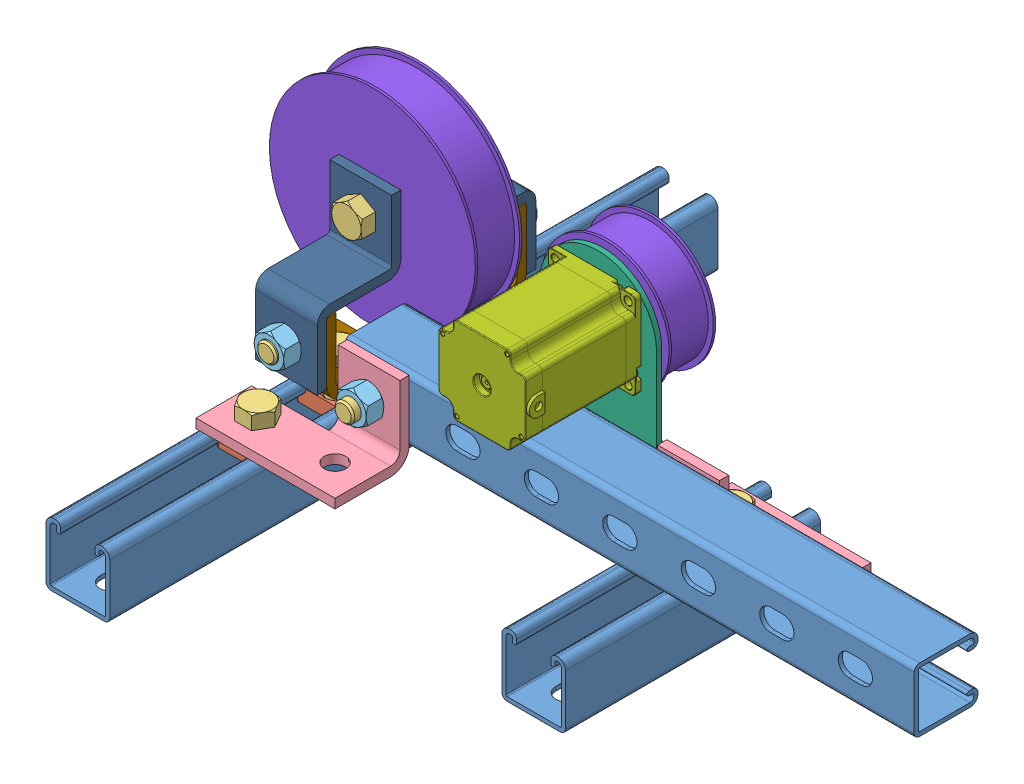
SolidWorks assembly Upper Pully System, configuration Default. Lengths in mm.
Overall size (490.87 222.78 393.7).
43 component instances, 10 part files, 44 mates.
Components (placement in the parent):
- P1000T - Unistrut Channel (Slots)-1: P1000T - Unistrut Channel (Slots) [0'-6.5"] at (-290.6524 -105.3852 -315.3895) size (41.28 41.27 165.1)
- Channel Nut-1: Channel Nut [P2223] at (-290.5427 -89.1071 -443.5385) x (1 0 0) z (0 1 0) size (34.99 19.63 34.65)
  - P3013 - Channel Nut-3: P3013 - Channel Nut [.5"] at origin size (34.99 19.63 9.53)
  - hex bolt_ai-1: hex bolt_ai [HBOLT 0.5000-13x1x1-N] at (0 0 19.555) x (0 0 -1) z (0 -1 0) size (34.65 22 19.05)
- P1000T - Unistrut Channel (Slots)-2: P1000T - Unistrut Channel (Slots) [1'-2.5"] at (-471.5246 -53.733 -394.9011) x (0.000688 1 0) z (-1 0.000688 0) size (41.28 41.27 368.3)
- Channel Nut-2: Channel Nut [P2223] at (-290.5427 -53.7478 -411.1791) x (0.000688 1 0) z (0 0 -1) size (34.99 19.63 34.65)
  - P3013 - Channel Nut-3: P3013 - Channel Nut [.5"] at origin size (34.99 19.63 9.53)
  - hex bolt_ai-1: hex bolt_ai [HBOLT 0.5000-13x1x1-N] at (0 0 19.555) x (0 0 -1) z (0 -1 0) size (34.65 22 19.05)
- P1038 - Unistrut 3-Hole 90 deg Fitting Variant-1: P1038 - Unistrut 3-Hole 90 deg Fitting Variant [Default] at (-220.5427 -84.7478 -463.5385) x (1 0 0) z (0 -1 0) size (90 48 51)
- P1000T - Unistrut Channel (Slots)-3: P1000T - Unistrut Channel (Slots) [1'-3.5"] at (-500.2028 -105.3852 -229.9119) size (41.28 41.27 393.7)
- Channel Nut-3: Channel Nut [P2245] at (-500.0933 -89.1071 -346.2637) x (1 0 0) z (0 1 0) size (34.99 19.63 34.65)
  - P3013 - Channel Nut-3: P3013 - Channel Nut [.5"] at origin size (34.99 19.63 9.53)
  - hex bolt_ai-1: hex bolt_ai [HBOLT 0.5000-13x1x1-N] at (0 0 19.9549) x (0 0 -1) z (0 -1 0) size (34.65 22 19.05)
- P1038 - Unistrut 3-Hole 90 deg Fitting Variant-2: P1038 - Unistrut 3-Hole 90 deg Fitting Variant [Default] at (-520.0933 -84.7478 -326.2637) x (-1 0 0) z (0 -1 0) size (90 48 51)
- hex bolt_ai-2: hex bolt_ai [HBOLT 0.5000-13x1x1-N] at (-450.0933 -53.7478 -386.1763) x (0 0 1) z (-1 0.000688 0) size (34.65 22 19.05)
- hex nut_ai-2: hex nut_ai [HNUT 0.5000-20-D-N] at (-450.0933 -53.7478 -356.8845) x (1 -0.000688 0) z (0 0 1) size (19.05 22 11.38)
- Channel Nut-4: Channel Nut [P2245+P1346] at (-500.0933 -89.1071 -473.178) x (1 0 0) z (0 1 0) size (34.99 19.63 35.49)
  - P3013 - Channel Nut-3: P3013 - Channel Nut [.5"] at origin size (34.99 19.63 9.53)
  - hex bolt_ai-1: hex bolt_ai [HBOLT 0.5000-13x1x1-N] at (0 0 25.9549) x (0 0 -1) z (0 -1 0) size (34.65 22 19.05)
- stepper motor mount-1: stepper motor mount [Default] at (-349.3295 17.8284 -418.8405) x (-1 0.000681 0) z (0 0 1) size (76.2 127 3.3)
- Channel Nut-5: Channel Nut [P2223] at (-325.8084 -53.9427 -411.1791) x (-0.000688 -1 0) z (0 0 -1) size (34.99 19.63 34.65)
  - P3013 - Channel Nut-3: P3013 - Channel Nut [.5"] at origin size (34.99 19.63 9.53)
  - hex bolt_ai-1: hex bolt_ai [HBOLT 0.5000-13x1x1-N] at (0 0 19.555) x (0 0 -1) z (0 -1 0) size (34.65 22 19.05)
- Channel Nut-6: Channel Nut [P2223] at (-372.9484 -53.9106 -411.1791) x (-0.000688 -1 0) z (0 0 -1) size (34.99 19.63 34.65)
  - P3013 - Channel Nut-3: P3013 - Channel Nut [.5"] at origin size (34.99 19.63 9.53)
  - hex bolt_ai-1: hex bolt_ai [HBOLT 0.5000-13x1x1-N] at (0 0 19.555) x (0 0 -1) z (0 -1 0) size (34.65 22 19.05)
- Stepper Motor NEMA 23HS7430-1: Stepper Motor NEMA 23HS7430 [По умолчанию] at (-349.3295 17.8284 -415.5385) x (1 -0.000681 0) z (0 0 1) size (58.4 56.4 95.6)
- Wide Pulley-1: Wide Pulley [3"x0.25"] at (-349.3295 17.8284 -435.5092) size (82.55 82.55 30.16)
- Large Pulley Mount-1: Large Pulley Mount [Default] at (-485.3304 -93.9054 -373.5693) x (0 1 0) z (1 0 0) size (187.97 168.14 187.97)
  - P1026 - Unistrut 2-Hole 90 deg Fitting-1: P1026 - Unistrut 2-Hole 90 deg Fitting [Default] at (18.6827 -44.2712 5.2371) size (50 47 40)
  - P1347 - Unistrut 2-Hole Z Fitting-1: P1347 - Unistrut 2-Hole Z Fitting [Default] at (28.6827 8.7288 -34.7629) x (1 0 0) z (0 0 -1) size (88 54 40)
  - hex bolt_ai-3: hex bolt_ai [HBOLT 0.5000-13x1x1-N] at (48.6827 -12.5168 -14.7629) x (0 1 0) z (0 0 1) size (34.65 22 19.05)
  - hex nut_ai-2: hex nut_ai [HNUT 0.5000-20-D-N] at (48.6827 20.108 -14.7629) x (0.866025 0 -0.5) z (0 1 0) size (19.05 22 11.38)
  - Wide Pulley-2: Wide Pulley [5"x0.5"] at (96.6827 -61.9399 -14.7629) x (0.762017 0 -0.647557) z (0 -1 0) size (133.35 133.35 30.16)
  - hex bolt_ai-2: hex bolt_ai [HBOLT 0.5000-20x3x3-N] at (96.6827 -30.0256 -14.7629) x (0 -1 0) z (0 0 1) size (85.45 22 19.05)
  - P1026 - Unistrut 2-Hole 90 deg Fitting-2: P1026 - Unistrut 2-Hole 90 deg Fitting [Default] at (18.6827 -79.6087 -34.7629) x (1 0 0) z (0 0 -1) size (50 47 40)
  - P1347 - Unistrut 2-Hole Z Fitting-2: P1347 - Unistrut 2-Hole Z Fitting [Default] at (28.6827 -132.6087 5.2371) size (88 54 40)
  - hex bolt_ai-4: hex bolt_ai [HBOLT 0.5000-13x1x1-N] at (48.6827 -111.3631 -14.7629) x (0 -1 0) z (0 0 -1) size (34.65 22 19.05)
  - hex nut_ai-3: hex nut_ai [HNUT 0.5000-20-D-N] at (48.6827 -132.6087 -14.7629) x (0.866025 0 -0.5) z (0 1 0) size (19.05 22 11.38)
  - hex nut_ai-4: hex nut_ai [HNUT 0.5000-20-D-N] at (96.6827 -95.9879 -14.7629) x (0.866025 0 0.5) z (0 -1 0) size (19.05 22 11.38)
- Channel Nut-7: Channel Nut [P2245+P1346] at (-500.0933 -89.1071 -397.8405) x (1 0 0) z (0 1 0) size (34.99 19.63 35.49)
  - P3013 - Channel Nut-3: P3013 - Channel Nut [.5"] at origin size (34.99 19.63 9.53)
  - hex bolt_ai-1: hex bolt_ai [HBOLT 0.5000-13x1x1-N] at (0 0 25.9549) x (0 0 -1) z (0 -1 0) size (34.65 22 19.05)
Mates (geometry in assembly coordinates):
- Coincident1: coincident anti-aligned: plane of P1000T - Unistrut Channel (Slots)-1 through (-279.5398 -90.5517 -480.4895) normal (-1 0 0); plane of Channel Nut-1/P3013 - Channel Nut-3 through (-279.5398 -90.8365 -434.0125) normal (1 0 0)
- Tangent1: tangent anti-aligned: cylinder of P1000T - Unistrut Channel (Slots)-1 through (-278.2062 -90.5517 -480.4895) axis (0 0 1) radius 1.3335; plane of Channel Nut-1/P3013 - Channel Nut-3 through (-277.1696 -91.8852 -434.0125) normal (0 1 0)
- Coincident2: coincident anti-aligned: plane of P1000T - Unistrut Channel (Slots)-2 through (-103.217 -42.8737 -409.7345) normal (-0.000688 -1 0); plane of Channel Nut-2/P3013 - Channel Nut-3 through (-300.0611 -42.7383 -409.4497) normal (0.000688 1 0)
- Tangent3: tangent anti-aligned: cylinder of P1000T - Unistrut Channel (Slots)-2 through (-103.2161 -41.5402 -409.7345) axis (-1 0.000688 0) radius 1.3335; plane of Channel Nut-2/P3013 - Channel Nut-3 through (-300.0595 -40.3681 -408.401) normal (0 0 -1)
- Concentric3: concentric anti-aligned: cylinder of Channel Nut-1/hex bolt_ai-1 through (-290.5427 -69.5521 -443.5385) axis (0 1 0) radius 6.35; cylinder of P1038 - Unistrut 3-Hole 90 deg Fitting Variant-1 through (-290.5427 -84.7478 -443.5385) axis (0 -1 0) radius 7
- Coincident5: coincident anti-aligned: plane of P1000T - Unistrut Channel (Slots)-1 through (-276.079 -84.7478 -480.4895) normal (0 1 0); plane of P1038 - Unistrut 3-Hole 90 deg Fitting Variant-1 through (-310.5427 -84.7478 -427.5385) normal (0 -1 0)
- Concentric4: concentric aligned: cylinder of Channel Nut-2/hex bolt_ai-1 through (-290.5427 -53.7478 -430.7341) axis (0 0 -1) radius 6.35; cylinder of P1038 - Unistrut 3-Hole 90 deg Fitting Variant-1 through (-290.5427 -53.7478 -421.5385) axis (0 0 -1) radius 7
- Coincident7: coincident anti-aligned: plane of P1000T - Unistrut Channel (Slots)-2 through (-103.2347 -68.5598 -415.5385) normal (0 0 -1); plane of P1038 - Unistrut 3-Hole 90 deg Fitting Variant-1 through (-310.5427 -33.7478 -415.5385) normal (0 0 1)
- Coincident8: coincident anti-aligned: plane of P1000T - Unistrut Channel (Slots)-3 through (-511.3154 -90.5517 -623.6119) normal (1 0 0); plane of Channel Nut-3/P3013 - Channel Nut-3 through (-511.3154 -89.1071 -336.7386) normal (-1 0 0)
- Tangent4: tangent anti-aligned: cylinder of P1000T - Unistrut Channel (Slots)-3 through (-512.6489 -90.5517 -623.6119) axis (0 0 1) radius 1.3335; plane of Channel Nut-3/P3013 - Channel Nut-3 through (-512.1202 -91.8852 -336.7386) normal (0 1 0)
- Coincident9: coincident aligned: plane of P1000T - Unistrut Channel (Slots)-1 through (-307.8293 -126.0226 -480.4895) normal (0 -1 0); plane of P1000T - Unistrut Channel (Slots)-3 through (-517.3797 -126.0226 -623.6119) normal (0 -1 0)
- Coincident11: coincident anti-aligned: plane of P1000T - Unistrut Channel (Slots)-3 through (-514.7762 -84.7478 -623.6119) normal (0 1 0); plane of P1038 - Unistrut 3-Hole 90 deg Fitting Variant-2 through (-430.0933 -84.7478 -362.2637) normal (0 -1 0)
- Concentric5: concentric aligned: cylinder of Channel Nut-3/hex bolt_ai-1 through (-500.0933 -69.1522 -346.2637) axis (0 1 0) radius 6.35; cylinder of P1038 - Unistrut 3-Hole 90 deg Fitting Variant-2 through (-500.0933 -78.7478 -346.2637) axis (0 1 0) radius 7
- Coincident12: coincident anti-aligned: plane of P1000T - Unistrut Channel (Slots)-2 through (-103.2365 -71.1632 -374.2637) normal (0 0 1); plane of P1038 - Unistrut 3-Hole 90 deg Fitting Variant-2 through (-430.0933 -33.7478 -374.2637) normal (0 0 -1)
- Concentric81: concentric anti-aligned: cylinder of P1000T - Unistrut Channel (Slots)-2 through (-450.0933 -53.7478 -415.5395) axis (0 0 1) radius 7.1437; cylinder of hex bolt_ai-2 through (-450.0933 -53.7478 -386.1763) axis (0 0 -1) radius 6.35
- Coincident141: coincident anti-aligned: plane of P1000T - Unistrut Channel (Slots)-2 through (-103.2129 -36.8095 -376.9307) normal (0 0 -1); plane of hex bolt_ai-2 through (-450.0858 -42.7492 -376.9307) normal (0 0 1)
- Concentric9: concentric anti-aligned: cylinder of P1038 - Unistrut 3-Hole 90 deg Fitting Variant-2 through (-450.0933 -53.7478 -368.2637) axis (0 0 1) radius 7; cylinder of hex bolt_ai-2 through (-450.0933 -53.7478 -386.1763) axis (0 0 -1) radius 6.35
- Concentric11: concentric anti-aligned: cylinder of hex bolt_ai-2 through (-450.0933 -53.7478 -386.1763) axis (0 0 -1) radius 6.35; cylinder of hex nut_ai-2 through (-450.0933 -53.7478 -368.2637) axis (0 0 1) radius 5.7544
- Coincident16: coincident anti-aligned: plane of P1038 - Unistrut 3-Hole 90 deg Fitting Variant-2 through (-470.0933 -72.7478 -368.2637) normal (0 0 1); plane of hex nut_ai-2 through (-450.0858 -42.7492 -368.2637) normal (0 0 -1)
- Coincident17: coincident aligned: plane of hex bolt_ai-2 through (-459.6146 -48.2419 -376.9307) normal (-1 0.000688 0); plane of hex nut_ai-2 through (-459.6146 -48.2419 -368.2637) normal (-1 0.000688 0)
- Parallel3: parallel aligned: plane of P1000T - Unistrut Channel (Slots)-2 through (-471.5364 -70.9099 -377.7244) normal (-1 0.000688 0); plane of hex bolt_ai-2 through (-459.6146 -48.2419 -376.9307) normal (-1 0.000688 0)
- Coincident19: coincident anti-aligned: plane of P1000T - Unistrut Channel (Slots)-3 through (-511.3154 -90.5517 -623.6119) normal (1 0 0); plane of Channel Nut-4/P3013 - Channel Nut-3 through (-511.3154 -89.1071 -463.653) normal (-1 0 0)
- Tangent7: tangent anti-aligned: cylinder of P1000T - Unistrut Channel (Slots)-3 through (-512.6489 -90.5517 -623.6119) axis (0 0 1) radius 1.3335; plane of Channel Nut-4/P3013 - Channel Nut-3 through (-512.1202 -91.8852 -463.653) normal (0 1 0)
- Coincident20: coincident anti-aligned: plane of P1000T - Unistrut Channel (Slots)-2 through (-103.217 -42.8737 -409.7345) normal (-0.000688 -1 0); plane of Channel Nut-5/P3013 - Channel Nut-3 through (-316.2757 -42.7271 -411.1791) normal (0.000688 1 0)
- Tangent8: tangent anti-aligned: cylinder of P1000T - Unistrut Channel (Slots)-2 through (-103.2161 -41.5402 -409.7345) axis (-1 0.000688 0) radius 1.3335; plane of Channel Nut-5/P3013 - Channel Nut-3 through (-316.2751 -41.9223 -408.401) normal (0 0 -1)
- Coincident21: coincident anti-aligned: plane of P1000T - Unistrut Channel (Slots)-2 through (-103.2323 -65.099 -409.7345) normal (0.000688 1 0); plane of Channel Nut-6/P3013 - Channel Nut-3 through (-363.43 -64.92 -409.4497) normal (-0.000688 -1 0)
- Tangent11: tangent anti-aligned: cylinder of P1000T - Unistrut Channel (Slots)-2 through (-103.2332 -66.4325 -409.7345) axis (-1 0.000688 0) radius 1.3335; plane of Channel Nut-6/P3013 - Channel Nut-3 through (-363.4316 -67.2902 -408.401) normal (0 0 -1)
- Concentric12: concentric aligned: cylinder of stepper motor mount-1 through (-372.9484 -53.9106 -415.5385) axis (0 0 -1) radius 7.112; cylinder of Channel Nut-6/hex bolt_ai-1 through (-372.9484 -53.9106 -430.7341) axis (0 0 -1) radius 6.35
- Concentric13: concentric aligned: cylinder of stepper motor mount-1 through (-325.8084 -53.9427 -415.5385) axis (0 0 -1) radius 7.112; cylinder of Channel Nut-5/hex bolt_ai-1 through (-325.8084 -53.9427 -430.7341) axis (0 0 -1) radius 6.35
- Coincident22: coincident anti-aligned: plane of P1000T - Unistrut Channel (Slots)-2 through (-103.2146 -39.4129 -415.5385) normal (0 0 -1); plane of stepper motor mount-1 through (-349.3295 17.8284 -415.5385) normal (0 0 1)
- Concentric14: concentric anti-aligned: circle of stepper motor mount-1; circle of Stepper Motor NEMA 23HS7430-1
- Coincident24: coincident anti-aligned: plane of stepper motor mount-1 through (-349.3295 17.8284 -415.5385) normal (0 0 1); plane of Stepper Motor NEMA 23HS7430-1 through (-349.3295 17.8284 -415.5385) normal (0 0 -1)
- Parallel6: parallel aligned: plane of stepper motor mount-1 through (-311.2295 17.8024 -415.5385) normal (1 -0.000681 0); plane of Stepper Motor NEMA 23HS7430-1 through (-321.1487 -10.3908 -405.5385) normal (1 -0.000681 0)
- Concentric17: concentric aligned: cylinder of Stepper Motor NEMA 23HS7430-1 through (-349.3295 17.8284 -436.1385) axis (0 0 1) radius 3.175; cylinder of Wide Pulley-1 through (-349.3295 17.8284 -450.5905) axis (0 0 1) radius 3.175
- Distance2: distance = 1.5875 mm anti-aligned: plane of Wide Pulley-1 through (-349.3295 17.8284 -420.428) normal (0 0 1); plane of stepper motor mount-1 through (-349.3295 17.8284 -418.8405) normal (0 0 -1)
- Coincident29: coincident: plane of P1000T - Unistrut Channel (Slots)-1 through (-311.2901 -89.796 -480.4895) normal (-1 0 0); point of stepper motor mount-1
- Coincident30: coincident anti-aligned: plane of P1000T - Unistrut Channel (Slots)-3 through (-511.3154 -90.5517 -623.6119) normal (1 0 0); plane of Channel Nut-7/P3013 - Channel Nut-3 through (-511.3154 -89.1071 -388.3155) normal (-1 0 0)
- Tangent13: tangent anti-aligned: plane of Channel Nut-7/P3013 - Channel Nut-3 through (-512.1202 -91.8852 -388.3155) normal (0 1 0); cylinder of P1000T - Unistrut Channel (Slots)-3 through (-512.6489 -90.5517 -623.6119) axis (0 0 1) radius 1.3335
- Concentric18: concentric anti-aligned: cylinder of Channel Nut-4/hex bolt_ai-1 through (-500.0933 -63.1522 -473.178) axis (0 1 0) radius 6.35; cylinder of Large Pulley Mount-1/P1026 - Unistrut 2-Hole 90 deg Fitting-2 through (-500.0933 -75.2228 -473.178) axis (0 -1 0) radius 7
- Concentric19: concentric anti-aligned: cylinder of Large Pulley Mount-1/P1026 - Unistrut 2-Hole 90 deg Fitting-1 through (-500.0933 -75.2228 -397.8405) axis (0 -1 0) radius 7; cylinder of Channel Nut-7/hex bolt_ai-1 through (-500.0933 -63.1522 -397.8405) axis (0 1 0) radius 6.35
- Distance3: distance = 9.525 mm anti-aligned: plane of Large Pulley Mount-1/P1026 - Unistrut 2-Hole 90 deg Fitting-1 through (-520.0933 -75.2228 -370.8405) normal (0 -1 0); plane of P1000T - Unistrut Channel (Slots)-3 through (-514.7762 -84.7478 -623.6119) normal (0 1 0)
- Coincident32: coincident aligned: plane of Large Pulley Mount-1; plane of assembly through (0 0 -435.5092) normal (0 0 1)
- Distance5: distance = 168.275 mm anti-aligned: plane of P1000T - Unistrut Channel (Slots)-1 through (-311.2901 -89.796 -480.4895) normal (-1 0 0); plane of P1000T - Unistrut Channel (Slots)-3 through (-479.5651 -89.796 -623.6119) normal (1 0 0)
- Distance9: distance = 188.1027 mm aligned: plane of P1000T - Unistrut Channel (Slots)-3 through (-517.3797 -122.5618 -623.6119) normal (0 0 -1); plane of Large Pulley Mount-1/Wide Pulley-2 through (-500.0933 2.7772 -435.5092) normal (0 0 -1)
